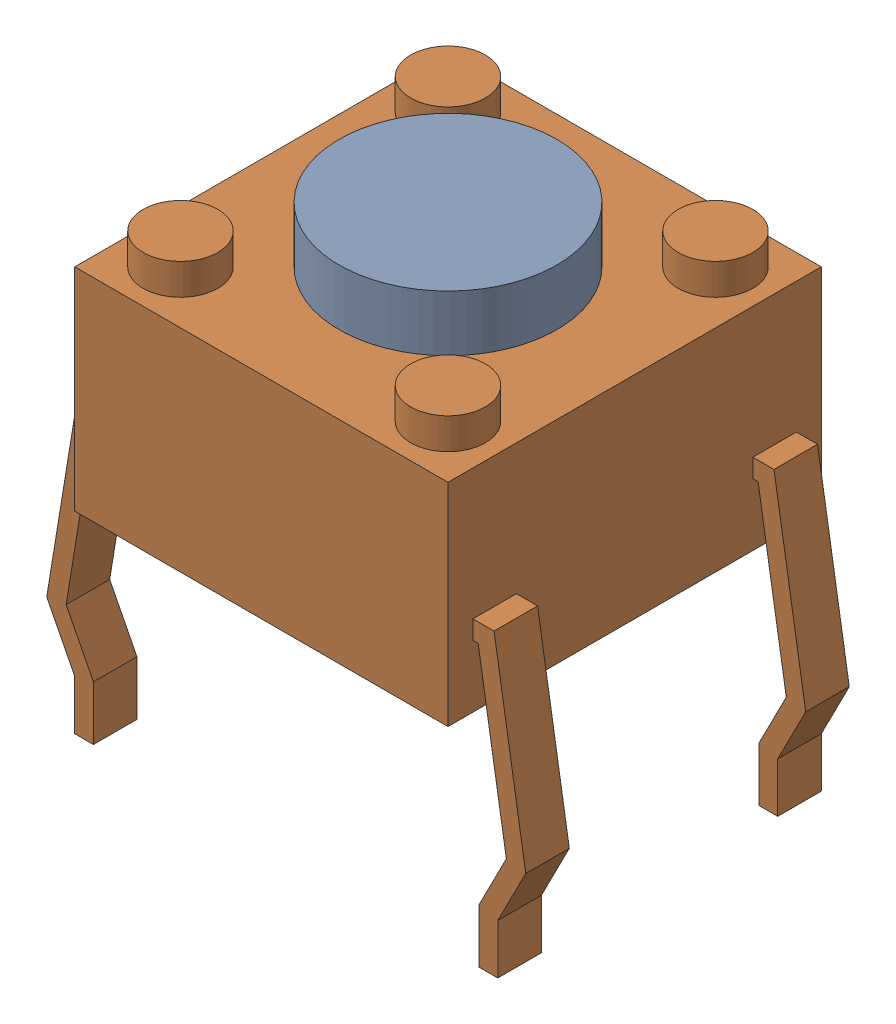
SolidWorks assembly OMRON-B3F_1000, configuration Default. Lengths in mm.
Overall size (7.7 7.8 6).
2 component instances, 2 part files, 0 mates.
Components (placement in the parent):
- OMRON-B3F_1000_B3F_1000_BUTTON-1: OMRON-B3F_1000_B3F_1000_BUTTON [Default] at (0 4.3 0) x (-1 0 0) z (0 0 -1) size (3.5 1 3.5)
- OMRON-B3F_1000_B3F_1000_BASE-1: OMRON-B3F_1000_B3F_1000_BASE [Default] at origin size (7.7 7.4 6)
